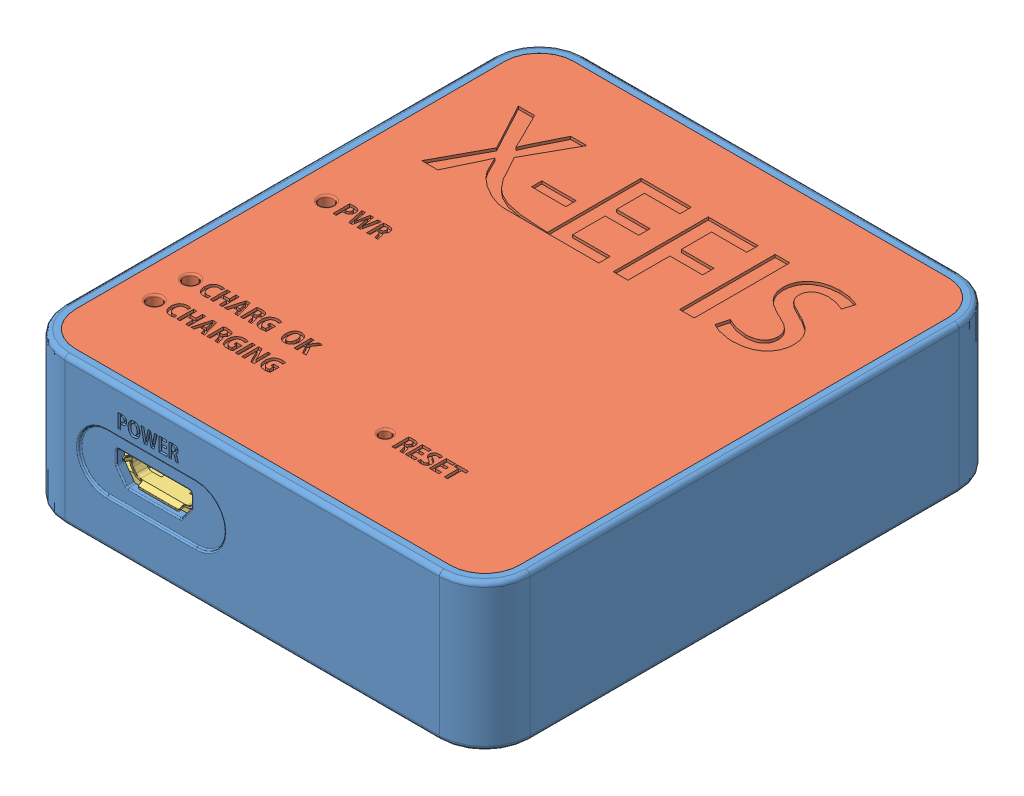
SolidWorks assembly BOX, configuration Default. Lengths in mm.
Overall size (51.4 16.25 57.4).
3 component instances, 3 part files, 5 mates.
Components (placement in the parent):
- CoverBox-1: CoverBox [Default] at (5.7198 24.2389 51.5426) size (51.4 16.2 57.4)
- BoxTop-1: BoxTop [Default] at (5.7198 39.2389 51.5426) x (1 0 0) z (0 0 -1) size (49 2.45 55)
- PCB1-2: PCB1 [Default] at (28.9805 29.9304 24.6813) x (-1 0 0) z (0 1 0) size (48.24 54.78 11.5)
Mates (geometry in assembly coordinates):
- 重合2: coincident anti-aligned: line of CoverBox-1 through (-14.9702 39.2389 79.0426) axis (1 0 0); line of BoxTop-1 through (26.4098 39.2389 79.0426) axis (-1 0 0)
- 重合3: coincident anti-aligned: line of CoverBox-1 through (30.2198 39.2389 75.2326) axis (0 0 -1); line of BoxTop-1 through (30.2198 39.2389 27.8526) axis (0 0 1)
- 重合6: coincident anti-aligned: plane of CoverBox-1 through (-14.5802 28.2389 74.5926) normal (0 1 0); plane of PCB1-2 through (28.9805 28.2389 28.4913) normal (0 -1 0)
- 同心3: concentric anti-aligned: circle of CoverBox-1; circle of PCB1-2
- 同心5: concentric anti-aligned: circle of PCB1-2; circle of CoverBox-1
